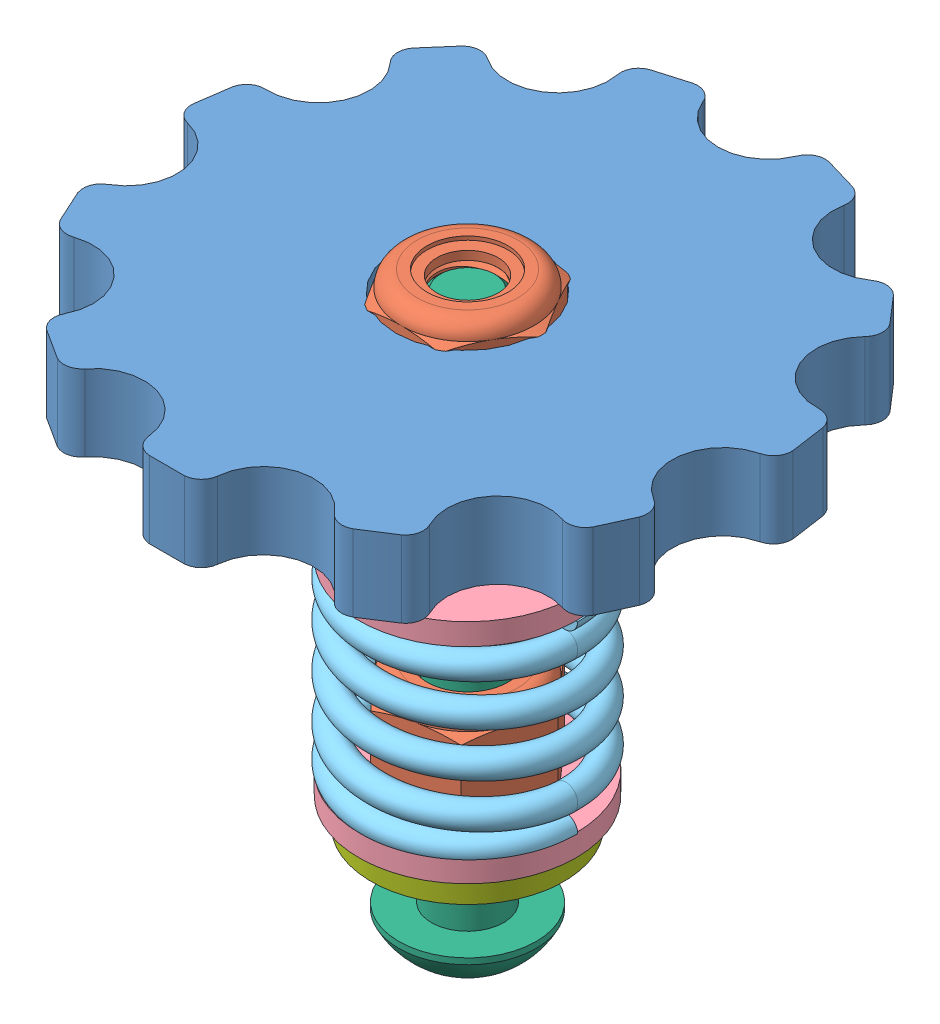
SolidWorks assembly Bed_Leveling_Wheel_Assembly, configuration Default. Lengths in mm.
Overall size (24.92 24.51 24.7).
9 component instances, 7 part files, 15 mates.
Components (placement in the parent):
- Bed Leveling Wheel-1: Bed Leveling Wheel [Default] at (-37.9125 35.3625 -5.2486) size (24.92 3.17 24.7)
- 3mm Nylock Nut-1: 3mm Nylock Nut [93625A100] at (-37.9125 35.3625 -5.2486) x (0 0 -1) z (1 0 0) size (5.5 4.1 6.35)
- 3mm Washer-1: 3mm Washer [93475A210] at (-37.9125 35.3625 -5.2486) x (1 0 0) z (0 -1 0) size (7 7 0.6)
- 3mm Oversized Washer (91116A120)-1: 3mm Oversized Washer (91116A120) [91116A120] at (-37.9125 28.966 -5.2486) x (1 0 0) z (0 1 0) size (9 9 0.9)
- 3mm Oversized Washer (91116A120)-2: 3mm Oversized Washer (91116A120) [91116A120] at (-37.9125 20.446 -5.2486) x (0.915956 0 -0.401278) z (0 1 0) size (9 9 0.9)
- Bed Spring (9657K275_Compressed)-1: Bed Spring (9657K275_Compressed) [9657K275] at (-37.9125 21.346 -5.2486) x (1 0 0) z (0 -1 0) size (9.43 9.55 8.14)
- 3mm Nylock Nut-2: 3mm Nylock Nut [93625A100] at (-37.9125 21.346 -5.2486) x (0.199963 0 0.979804) z (-0.979804 0 0.199963) size (5.5 4.1 6.35)
- 3mm x 22mm Buttonhead-2: 3mm x 22mm Buttonhead [92095A473] at (-37.9125 14.9668 -5.2486) x (0.150784 0 -0.988567) z (0 -1 0) size (5.7 5.7 23.77)
- 3mm Nylon Washer (95610A330)-1: 3mm Nylon Washer (95610A330) [95610A330] at (-37.9125 19.346 -5.2486) x (0.992764 0 0.120078) z (0 1 0) size (8 8 1.1)
Mates (geometry in assembly coordinates):
- Concentric1: concentric aligned: cylinder of Bed Leveling Wheel-1 through (-37.9125 38.5375 -5.2486) axis (0 -1 0) radius 2.975; cylinder of 3mm Nylock Nut-1 through (-37.9125 38.7721 -5.2486) axis (0 -1 0) radius 1.269
- Coincident1: coincident aligned: plane of Bed Leveling Wheel-1 through (-37.9125 35.3625 -5.2486) normal (0 -1 0); plane of 3mm Nylock Nut-1 through (-42.6756 35.3625 -2.4986) normal (0 -1 0)
- Parallel1: parallel aligned: plane of 3mm Nylock Nut-1 through (-39.5002 39.3625 -2.4986) normal (0 0 1); plane of assembly through (0 0 0) normal (0 0 1)
- Concentric2: concentric anti-aligned: cylinder of Bed Leveling Wheel-1 through (-37.9125 38.5375 -5.2486) axis (0 -1 0) radius 2.975; cylinder of 3mm Washer-1 through (-37.9125 34.7625 -5.2486) axis (0 1 0) radius 1.6
- Coincident3: coincident anti-aligned: plane of Bed Leveling Wheel-1 through (-37.9125 35.3625 -5.2486) normal (0 -1 0); plane of 3mm Washer-1 through (-37.9125 35.3625 -5.2486) normal (0 1 0)
- Concentric3: concentric anti-aligned: cylinder of Bed Leveling Wheel-1 through (-37.9125 38.5375 -5.2486) axis (0 -1 0) radius 2.975; cylinder of 3mm x 22mm Buttonhead-2 through (-37.9125 38.6168 -5.2486) axis (0 1 0) radius 1.5
- Concentric4: concentric anti-aligned: cylinder of 3mm Oversized Washer (91116A120)-1 through (-37.9125 29.866 -5.2486) axis (0 -1 0) radius 1.6; cylinder of 3mm x 22mm Buttonhead-2 through (-37.9125 38.6168 -5.2486) axis (0 1 0) radius 1.5
- Concentric5: concentric anti-aligned: cylinder of 3mm Oversized Washer (91116A120)-2 through (-37.9125 21.346 -5.2486) axis (0 -1 0) radius 1.6; cylinder of 3mm x 22mm Buttonhead-2 through (-37.9125 38.6168 -5.2486) axis (0 1 0) radius 1.5
- Concentric6: concentric anti-aligned: line of Bed Spring (9657K275_Compressed)-1 through (-37.9125 29.373 -5.2486) axis (0 -1 0); cylinder of 3mm x 22mm Buttonhead-2 through (-37.9125 38.6168 -5.2486) axis (0 1 0) radius 1.5
- Coincident4: coincident anti-aligned: plane of 3mm Oversized Washer (91116A120)-2 through (-37.9125 21.346 -5.2486) normal (0 1 0); plane of Bed Spring (9657K275_Compressed)-1 through (-37.9125 21.346 -5.2486) normal (0 -1 0)
- Coincident5: coincident anti-aligned: plane of 3mm Oversized Washer (91116A120)-1 through (-37.9125 28.966 -5.2486) normal (0 -1 0); plane of Bed Spring (9657K275_Compressed)-1 through (-37.9125 28.966 -5.2486) normal (0 1 0)
- Concentric7: concentric anti-aligned: cylinder of 3mm Nylock Nut-2 through (-37.9125 24.7555 -5.2486) axis (0 -1 0) radius 1.269; cylinder of 3mm x 22mm Buttonhead-2 through (-37.9125 38.6168 -5.2486) axis (0 1 0) radius 1.5
- Concentric8: concentric anti-aligned: cylinder of 3mm x 22mm Buttonhead-2 through (-37.9125 38.6168 -5.2486) axis (0 1 0) radius 1.5; cylinder of 3mm Nylon Washer (95610A330)-1 through (-37.9125 20.446 -5.2486) axis (0 -1 0) radius 1.6
- Coincident8: coincident anti-aligned: plane of 3mm Oversized Washer (91116A120)-2 through (-37.9125 21.346 -5.2486) normal (0 1 0); plane of 3mm Nylock Nut-2 through (-33.7954 21.346 -8.8955) normal (0 -1 0)
- Coincident9: coincident anti-aligned: plane of 3mm Oversized Washer (91116A120)-2 through (-37.9125 20.446 -5.2486) normal (0 -1 0); plane of 3mm Nylon Washer (95610A330)-1 through (-37.9125 20.446 -5.2486) normal (0 1 0)
